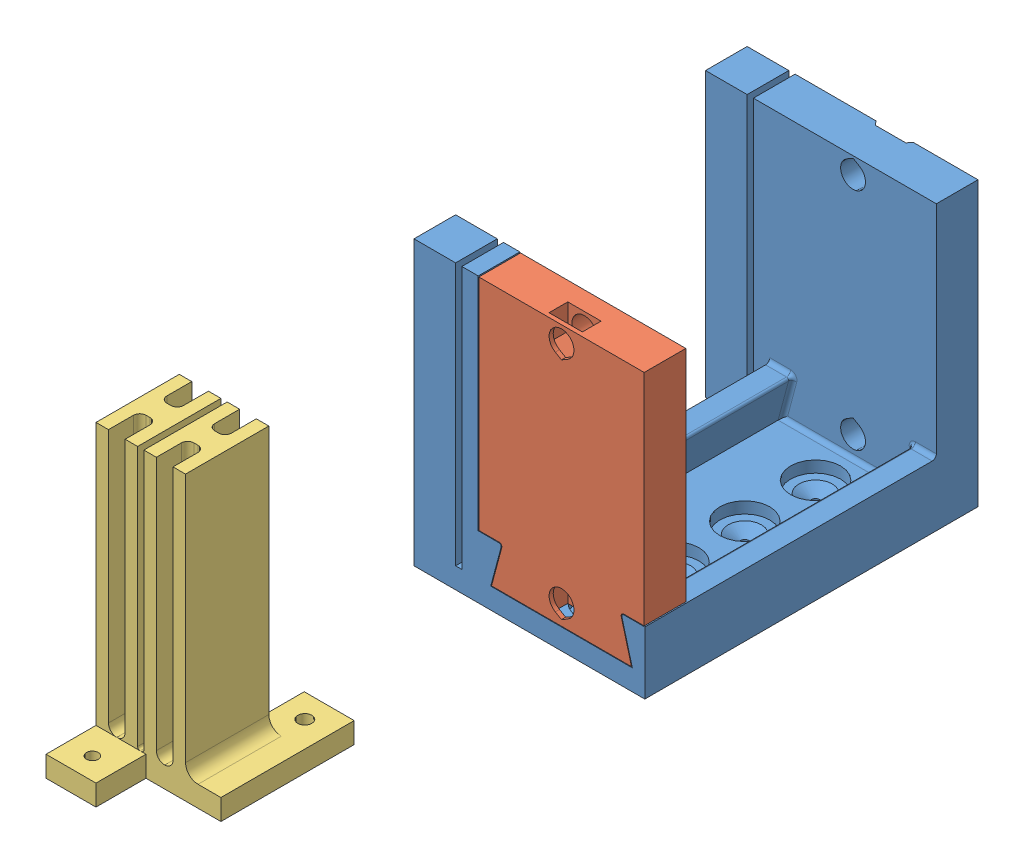
SolidWorks assembly Imadlo_v2, configuration Domyślna. Lengths in mm.
Overall size (55.43 68 168.35).
3 component instances, 3 part files, 10 mates.
Components (placement in the parent):
- Część1^Imadlo_v2-1: Część1^Imadlo_v2 [Domyślna] at origin size (55.43 68 80) (virtual)
- Część2^Imadlo_v2-1: Część2^Imadlo_v2 [Domyślna] at (0 0 80) size (39.7 62.7 10) (virtual)
- Część3^Imadlo_v2-1: Część3^Imadlo_v2 [Domyślna] at (6.5 -5 4.3526) x (-1 0 0) z (0 0 1) size (30 68 44) (virtual)
Mates (geometry in assembly coordinates):
- Ustalone1: in place: plane of Część1^Imadlo_v2-1 through (0 0 0) normal (0 0 1); moOrthogonalPlaneRef_w of Część1^Imadlo_v2-1 through (0 0 0) normal (0 1 0); plane of Część1^Imadlo_v2-1 through (0 0 0) normal (1 0 0); unknown of Część1^Imadlo_v2-1
- Wspólnie1: coincident aligned: plane of Część1^Imadlo_v2-1; plane of assembly
- Wspólnie2: coincident aligned: plane of Część1^Imadlo_v2-1 through (0 0 0) normal (0 1 0); moOrthogonalPlaneRef_w of assembly
- Wspólnie3: coincident anti-aligned: plane of Część1^Imadlo_v2-1 through (0 0 0) normal (1 0 0); moOrthogonalPlaneRef_w of assembly
- Ustalone2: in place: plane of Część1^Imadlo_v2-1 through (6.2071 7 80) normal (0 0 1); plane of Część2^Imadlo_v2-1 through (0 0 80) normal (0 0 1); plane of Część1^Imadlo_v2-1 through (6.2071 7 80) normal (0 0 1); plane of Część2^Imadlo_v2-1 through (0 0 80) normal (0 1 0); plane of Część1^Imadlo_v2-1 through (6.2071 7 80) normal (0 0 1); plane of Część2^Imadlo_v2-1 through (0 0 80) normal (1 0 0); plane of Część1^Imadlo_v2-1 through (14.9721 7 80) normal (0 0 1); unknown of Część2^Imadlo_v2-1
- Wspólnie4: coincident aligned: plane of Część1^Imadlo_v2-1; plane of Część2^Imadlo_v2-1
- Wspólnie5: coincident aligned: moOrthogonalPlaneRef_w of Część1^Imadlo_v2-1 through (0 0 80) normal (0 1 0); plane of Część2^Imadlo_v2-1 through (0 0 80) normal (0 1 0)
- Wspólnie6: coincident anti-aligned: moOrthogonalPlaneRef_w of Część1^Imadlo_v2-1 through (0 0 80) normal (-1 0 0); plane of Część2^Imadlo_v2-1 through (0 0 80) normal (1 0 0)
- Wspólnie2: coincident aligned: plane of Część1^Imadlo_v2-1 through (-35.4295 -25.8867 80) normal (-1 0 0); plane of Część3^Imadlo_v2-1 through (-35.4295 50.7541 136.3526) normal (-1 0 0)
- Wspólnie3: coincident aligned: plane of Część1^Imadlo_v2-1 through (-20 -7.5 80) normal (0 -1 0); plane of Część3^Imadlo_v2-1 through (6.5 -7.5 4.3526) normal (0 -1 0)
